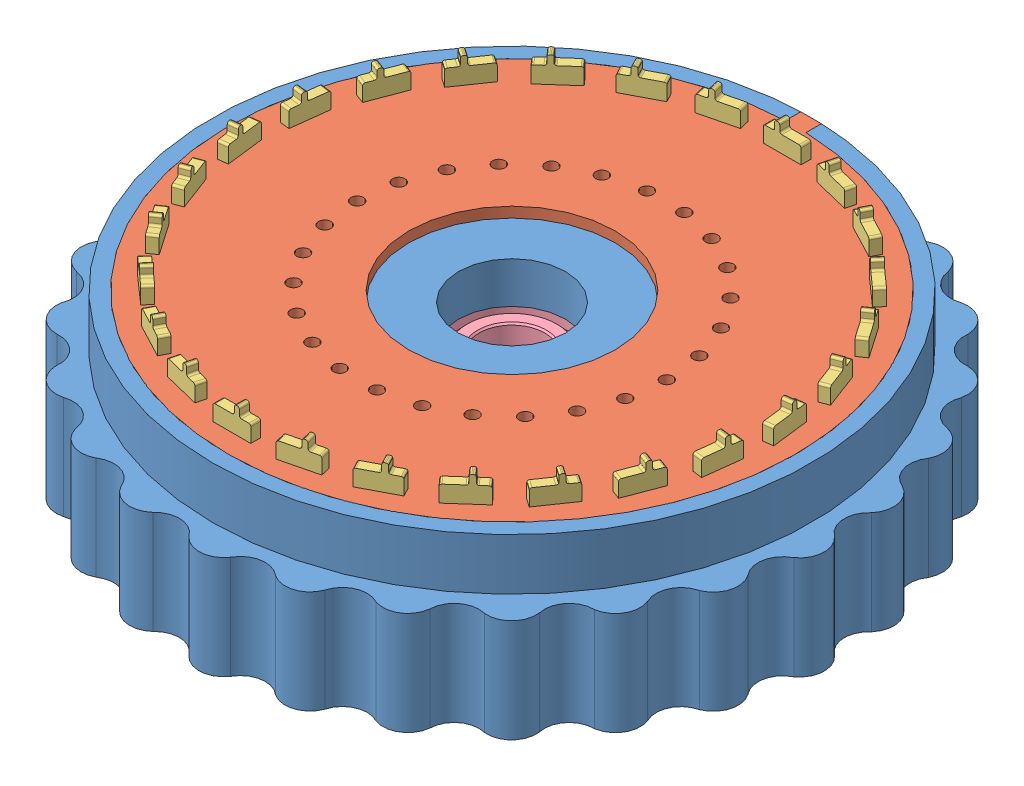
SolidWorks assembly Letter selection wheel assembly, configuration Default. Lengths in mm.
Overall size (72.37 17.5 74.83).
31 component instances, 4 part files, 11 mates.
Components (placement in the parent):
- Letter selection wheel-1: Letter selection wheel [Default] at (26.602 23.0199 46.072) size (64.18 15 64.19)
- PCB assembly-1: PCB assembly [Default] at (20.8498 33.5038 101.5951) x (1 0 0) z (0 1 0) size (67.78 70.24 3.5)
  - selector wheel PCB-2: selector wheel PCB [Default] at (5.7522 55.5231 3.5161) size (67.78 70.24 1)
  - spring pin-27: spring pin [Default] at (7.3927 81.0239 5.3161) x (1 0 0) z (0 -1 0) size (3.66 2.5 0.96)
  - spring pin-28: spring pin [Default] at (1.2423 80.6755 5.3161) x (0.970942 0.239316 0) z (0.239316 -0.970942 0) size (3.66 2.5 0.96)
  - spring pin-29: spring pin [Default] at (-4.6461 78.8653 5.3161) x (0.885456 0.464723 0) z (0.464723 -0.885456 0) size (3.66 2.5 0.96)
  - spring pin-30: spring pin [Default] at (-9.9301 75.6986 5.3161) x (0.748511 0.663123 0) z (0.663123 -0.748511 0) size (3.66 2.5 0.96)
  - spring pin-31: spring pin [Default] at (-14.3027 71.3593 5.3161) x (0.568065 0.822984 0) z (0.822984 -0.568065 0) size (3.66 2.5 0.96)
  - spring pin-32: spring pin [Default] at (-17.5098 66.0997 5.3161) x (0.354605 0.935016 0) z (0.935016 -0.354605 0) size (3.66 2.5 0.96)
  - spring pin-33: spring pin [Default] at (-19.365 60.2254 5.3161) x (0.120537 0.992709 0) z (0.992709 -0.120537 0) size (3.66 2.5 0.96)
  - spring pin-34: spring pin [Default] at (-19.7605 54.0778 5.3161) x (-0.120537 0.992709 0) z (0.992709 0.120537 0) size (3.66 2.5 0.96)
  - spring pin-35: spring pin [Default] at (-18.6732 48.0142 5.3161) x (-0.354605 0.935016 0) z (0.935016 0.354605 0) size (3.66 2.5 0.96)
  - spring pin-36: spring pin [Default] at (-16.1665 42.3871 5.3161) x (-0.568065 0.822984 0) z (0.822984 0.568065 0) size (3.66 2.5 0.96)
  - spring pin-37: spring pin [Default] at (-12.3859 37.5233 5.3161) x (-0.748511 0.663123 0) z (0.663123 0.748511 0) size (3.66 2.5 0.96)
  - spring pin-38: spring pin [Default] at (-7.5512 33.7056 5.3161) x (-0.885456 0.464723 0) z (0.464723 0.885456 0) size (3.66 2.5 0.96)
  - spring pin-39: spring pin [Default] at (-1.9434 31.1559 5.3161) x (-0.970942 0.239316 0) z (0.239316 0.970942 0) size (3.66 2.5 0.96)
  - spring pin-40: spring pin [Default] at (4.1117 30.0223 5.3161) x (-1 0 0) z (0 1 0) size (3.66 2.5 0.96)
  - spring pin-41: spring pin [Default] at (10.2621 30.3707 5.3161) x (-0.970942 -0.239316 0) z (-0.239316 0.970942 0) size (3.66 2.5 0.96)
  - spring pin-42: spring pin [Default] at (16.1505 32.1809 5.3161) x (-0.885456 -0.464723 0) z (-0.464723 0.885456 0) size (3.66 2.5 0.96)
  - spring pin-43: spring pin [Default] at (21.4345 35.3476 5.3161) x (-0.748511 -0.663123 0) z (-0.663123 0.748511 0) size (3.66 2.5 0.96)
  - spring pin-44: spring pin [Default] at (25.8071 39.6869 5.3161) x (-0.568065 -0.822984 0) z (-0.822984 0.568065 0) size (3.66 2.5 0.96)
  - spring pin-45: spring pin [Default] at (29.0142 44.9465 5.3161) x (-0.354605 -0.935016 0) z (-0.935016 0.354605 0) size (3.66 2.5 0.96)
  - spring pin-46: spring pin [Default] at (30.8694 50.8208 5.3161) x (-0.120537 -0.992709 0) z (-0.992709 0.120537 0) size (3.66 2.5 0.96)
  - spring pin-47: spring pin [Default] at (31.2649 56.9684 5.3161) x (0.120537 -0.992709 0) z (-0.992709 -0.120537 0) size (3.66 2.5 0.96)
  - spring pin-48: spring pin [Default] at (30.1776 63.032 5.3161) x (0.354605 -0.935016 0) z (-0.935016 -0.354605 0) size (3.66 2.5 0.96)
  - spring pin-49: spring pin [Default] at (27.6709 68.6591 5.3161) x (0.568065 -0.822984 0) z (-0.822984 -0.568065 0) size (3.66 2.5 0.96)
  - spring pin-50: spring pin [Default] at (23.8903 73.5229 5.3161) x (0.748511 -0.663123 0) z (-0.663123 -0.748511 0) size (3.66 2.5 0.96)
  - spring pin-51: spring pin [Default] at (19.0556 77.3406 5.3161) x (0.885456 -0.464723 0) z (-0.464723 -0.885456 0) size (3.66 2.5 0.96)
  - spring pin-52: spring pin [Default] at (13.4478 79.8903 5.3161) x (0.970942 -0.239316 0) z (-0.239316 -0.970942 0) size (3.66 2.5 0.96)
- selector wheel PCB-3: selector wheel PCB [Default] at (26.602 23.0199 46.072) x (1 0 0) z (0 1 0) size (67.78 70.24 1)
- 57155K356 ball bearing-1: 57155K356 ball bearing [57155K356] at (26.602 31.4324 46.072) x (1 0 0) z (0 -1 0) size (12.7 12.7 3.17)
Mates (geometry in assembly coordinates):
- Coincident5: coincident: plane of Letter selection wheel-1 through (26.602 37.0199 46.072) normal (0 1 0); plane of ? through (26.602 37.0199 46.072) normal (0 -1 0)
- Concentric4: concentric: cylinder of Letter selection wheel-1 through (26.602 37.0199 46.072) axis (0 1 0) radius 27.5; cylinder of ? through (26.602 38.0199 46.072) axis (0 -1 0) radius 27.5
- Coincident8: coincident anti-aligned: plane of Letter selection wheel-1 through (25.602 37.0199 18.5902) normal (1 0 0); plane of PCB assembly-1/selector wheel PCB-2 through (25.602 38.0199 18.5902) normal (-1 0 0)
- Coincident9: coincident anti-aligned: plane of Letter selection wheel-1 through (26.602 37.0199 46.072) normal (0 1 0); plane of PCB assembly-1/selector wheel PCB-2 through (26.602 37.0199 46.072) normal (0 -1 0)
- Concentric6: concentric anti-aligned: cylinder of Letter selection wheel-1 through (26.602 37.0199 46.072) axis (0 1 0) radius 27.5; cylinder of PCB assembly-1/selector wheel PCB-2 through (26.602 38.0199 46.072) axis (0 -1 0) radius 27.5
- Coincident10: coincident anti-aligned: plane of Letter selection wheel-1 through (25.602 37.0199 18.5902) normal (1 0 0); plane of PCB assembly-1/selector wheel PCB-2 through (25.602 38.0199 18.5902) normal (-1 0 0)
- Concentric7: concentric aligned: cylinder of Letter selection wheel-1 through (26.602 24.0199 46.072) axis (0 -1 0) radius 27.5; cylinder of selector wheel PCB-3 through (26.602 24.0199 46.072) axis (0 -1 0) radius 27.5
- Coincident13: coincident anti-aligned: plane of Letter selection wheel-1 through (26.602 24.0199 46.072) normal (0 -1 0); plane of selector wheel PCB-3 through (26.602 24.0199 46.072) normal (0 1 0)
- Coincident14: coincident anti-aligned: plane of Letter selection wheel-1 through (27.602 24.0199 18.5902) normal (-1 0 0); plane of selector wheel PCB-3 through (27.602 24.0199 17.0902) normal (1 0 0)
- Concentric9: concentric anti-aligned: cylinder of Letter selection wheel-1 through (26.602 23.0199 46.072) axis (0 1 0) radius 5.18; cylinder of 57155K356 ball bearing-1 through (26.602 29.8449 46.072) axis (0 -1 0) radius 6.35
- Coincident15: coincident anti-aligned: plane of Letter selection wheel-1 through (59.2498 33.0199 44.121) normal (0 -1 0); plane of 57155K356 ball bearing-1 through (26.602 33.0199 52.2633) normal (0 1 0)
